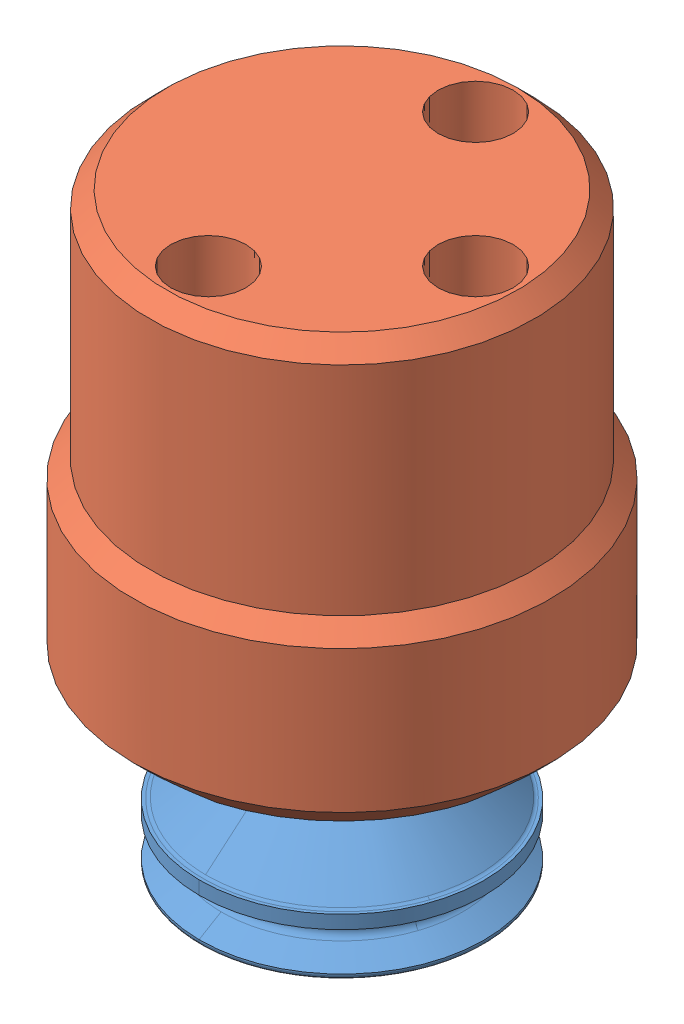
SolidWorks assembly SCARA_endeffektor, configuration Standard. Lengths in mm.
Overall size (24.3 35 25).
2 component instances, 2 part files, 5 mates.
Components (placement in the parent):
- ZP3_T16BNK3_04_8-1: ZP3_T16BNK3_04_8 [Default] at (0 -35 0) x (0.999977 0 0.006758) z (-0.006758 0 0.999977) size (17 10 17)
- saugerdruck-1: saugerdruck [Standard] at origin size (24.3 29.5 25)
Mates (geometry in assembly coordinates):
- Konzentrisch1: concentric aligned: cylinder of ZP3_T16BNK3_04_8-1 through (0 -35 0) axis (0 -1 0) radius 1.5; cylinder of saugerdruck-1 through (0 0 0) axis (0 -1 0) radius 2.5
- Deckungsgleich1: coincident anti-aligned: plane of ZP3_T16BNK3_04_8-1 through (4.4999 -25 0.0304) normal (0 1 0); plane of saugerdruck-1 through (-12.5 -25 0) normal (0 -1 0)
- Deckungsgleich2: coincident aligned: plane of saugerdruck-1 through (0 0 0) normal (0 0 1)
- Deckungsgleich3: coincident aligned: plane of saugerdruck-1 through (0 0 0) normal (0 1 0)
- Deckungsgleich4: coincident aligned: plane of saugerdruck-1 through (0 0 0) normal (1 0 0)
